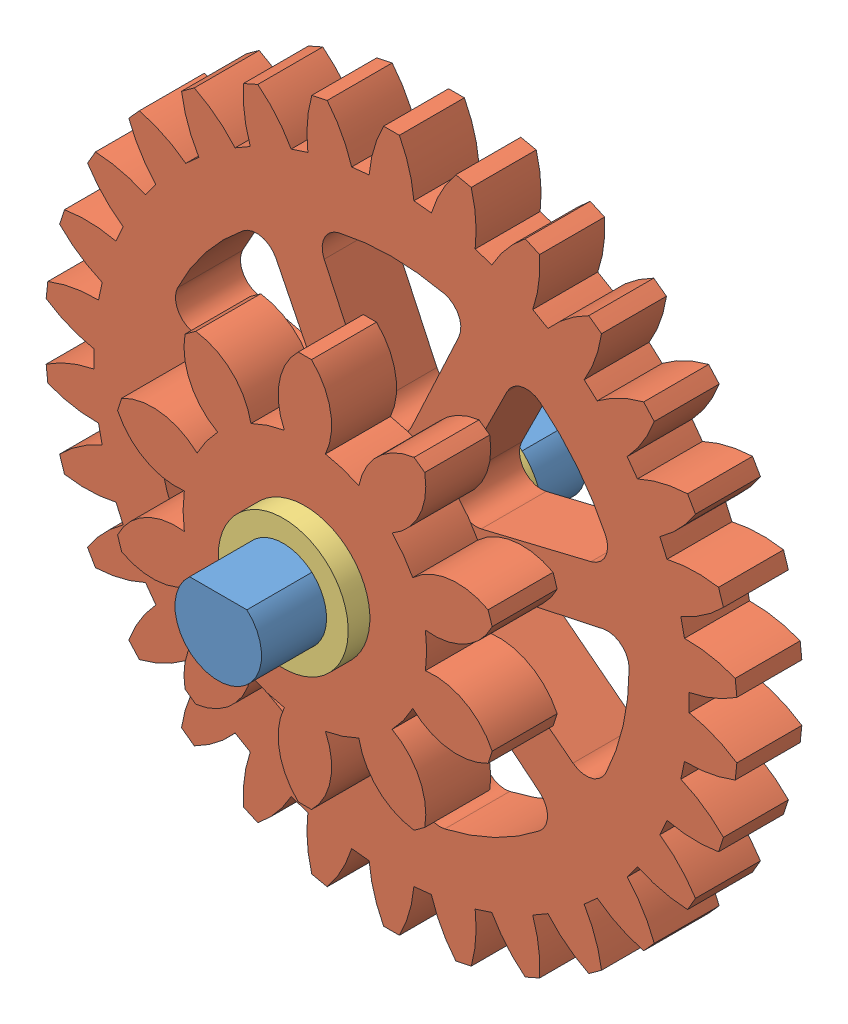
SolidWorks assembly subassem2, configuration Default. Lengths in mm.
Overall size (31.89 32 15).
6 component instances, 3 part files, 12 mates.
Components (placement in the parent):
- axle-1: axle [Short] at (-5.5643 11.0888 23.9371) size (4 3.5 15)
- root_gear-2: root_gear [30T 1.0Mod] at (-5.5643 11.0888 30.9371) x (-1 0 0) z (0 0 -1) size (31.89 32 3)
- root_gear-3: root_gear [10T 1.5Mod] at (-5.5643 11.0888 31.9371) size (17.3 18 3)
- spacer-1: spacer [1mm Tall] at (-5.5643 11.0888 34.9371) size (6 6 1)
- spacer-2: spacer [1mm Tall] at (-5.5643 11.0888 30.9371) size (6 6 1)
- spacer-3: spacer [4.2mm ID] at (-5.5643 11.0888 26.9371) size (6 6 1)
Mates (geometry in assembly coordinates):
- Concentric3: concentric aligned: cylinder of axle-1 through (-5.5643 11.0888 38.9371) axis (0 0 -1) radius 2; cylinder of spacer-1 through (-5.5643 11.0888 35.9371) axis (0 0 -1) radius 2
- Distance1: distance = 3 mm aligned: plane of spacer-1 through (-5.5643 11.0888 35.9371) normal (0 0 1); plane of axle-1 through (-5.5643 11.0888 38.9371) normal (0 0 1)
- Coincident3: coincident anti-aligned: plane of root_gear-3 through (-5.5643 11.0888 34.9371) normal (0 0 1); plane of spacer-1 through (-5.5643 11.0888 34.9371) normal (0 0 -1)
- Coincident4: coincident anti-aligned: plane of axle-1 through (-6.8872 12.5888 38.9371) normal (0 1 0); plane of root_gear-3 through (-4.2414 12.5888 41.9371) normal (0 -1 0)
- Concentric4: concentric aligned: cylinder of axle-1 through (-5.5643 11.0888 38.9371) axis (0 0 -1) radius 2; cylinder of root_gear-3 through (-5.5643 11.0888 41.9371) axis (0 0 -1) radius 2
- Concentric5: concentric: cylinder of axle-1 through (-5.5643 11.0888 38.9371) axis (0 0 -1) radius 2; cylinder of spacer-2 through (-5.5643 11.0888 31.9371) axis (0 0 -1) radius 2
- Coincident5: coincident anti-aligned: plane of root_gear-3 through (-5.5643 11.0888 31.9371) normal (0 0 -1); plane of spacer-2 through (-5.5643 11.0888 31.9371) normal (0 0 1)
- Coincident7: coincident anti-aligned: plane of root_gear-2 through (-5.5643 11.0888 30.9371) normal (0 0 1); plane of spacer-2 through (-5.5643 11.0888 30.9371) normal (0 0 -1)
- Coincident8: coincident anti-aligned: plane of axle-1 through (-6.8872 12.5888 38.9371) normal (0 1 0); plane of root_gear-2 through (-6.8872 12.5888 20.9371) normal (0 -1 0)
- Coincident9: coincident anti-aligned: plane of root_gear-2 through (-5.5643 11.0888 27.9371) normal (0 0 -1); plane of spacer-3 through (-5.5643 11.0888 27.9371) normal (0 0 1)
- Concentric6: concentric aligned: cylinder of axle-1 through (-5.5643 11.0888 38.9371) axis (0 0 -1) radius 2; cylinder of spacer-3 through (-5.5643 11.0888 27.9371) axis (0 0 -1) radius 2
- Concentric7: concentric anti-aligned: cylinder of axle-1 through (-5.5643 11.0888 38.9371) axis (0 0 -1) radius 2; cylinder of root_gear-2 through (-5.5643 11.0888 20.9371) axis (0 0 1) radius 2
